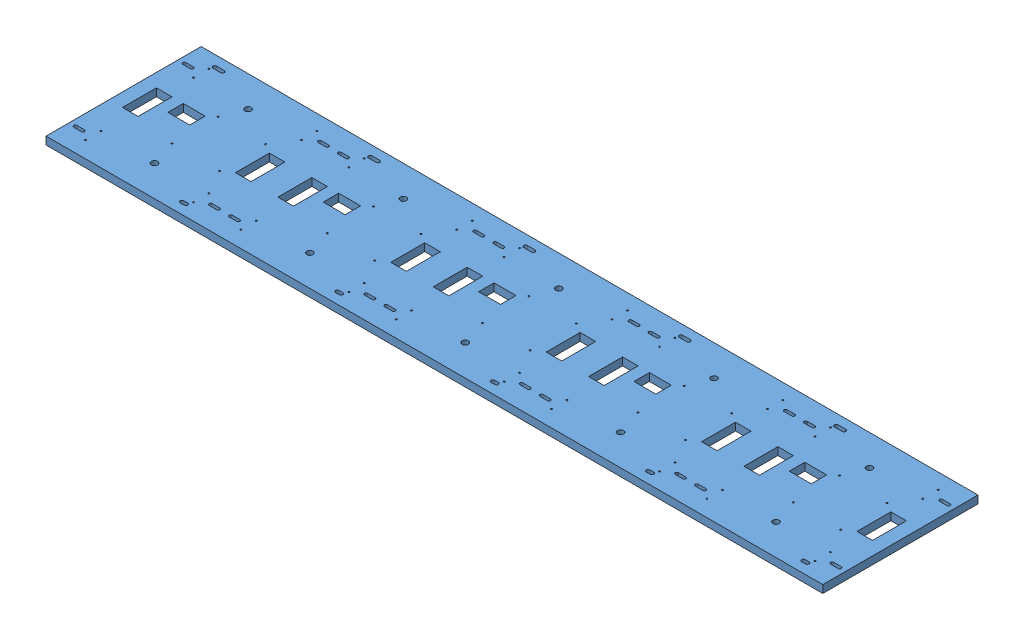
SolidWorks assembly Assem2, configuration Default. Lengths in mm.
Overall size (639.95 6.35 127.84).
6 component instances, 2 part files, 16 mates.
Components (placement in the parent):
- MDF-1: MDF [Default] at (-109.0147 9.1938 79.272) size (127.99 6.35 127.84) (hidden)
- MDF-2: MDF [Default] at (-237.0053 9.1938 79.272) size (127.99 6.35 127.84) (hidden)
- MDF-3: MDF [Default] at (18.9759 9.1938 79.272) size (127.99 6.35 127.84) (hidden)
- MDF-4: MDF [Default] at (274.9571 9.1938 79.272) size (127.99 6.35 127.84) (hidden)
- MDF-5: MDF [Default] at (146.9665 9.1938 79.272) size (127.99 6.35 127.84) (hidden)
- Part4^Assem2-1: Part4^Assem2 [Default] at (146.9665 15.5438 79.272) x (1 0 0) z (0 1 0) size (639.95 127.84 6.35) (virtual)
Mates (geometry in assembly coordinates):
- Coincident1: coincident aligned: plane of MDF-1 through (-109.0147 15.5438 79.272) normal (0 1 0); plane of MDF-2 through (-237.0053 15.5438 79.272) normal (0 1 0)
- Coincident2: coincident aligned: plane of MDF-1 through (-109.0147 15.5438 79.272) normal (0 0 1); plane of MDF-2 through (-237.0053 15.5438 79.272) normal (0 0 1)
- Coincident3: coincident anti-aligned: plane of MDF-1 through (-109.0147 15.5438 79.272) normal (-1 0 0); plane of MDF-2 through (-109.0147 15.5438 79.272) normal (1 0 0)
- Coincident4: coincident aligned: plane of MDF-1 through (-109.0147 15.5438 79.272) normal (0 1 0); plane of MDF-3 through (18.9759 15.5438 79.272) normal (0 1 0)
- Coincident5: coincident aligned: plane of MDF-1 through (-109.0147 15.5438 79.272) normal (0 0 1); plane of MDF-3 through (18.9759 15.5438 79.272) normal (0 0 1)
- Coincident6: coincident anti-aligned: plane of MDF-1 through (18.9759 15.5438 79.272) normal (1 0 0); plane of MDF-3 through (18.9759 15.5438 79.272) normal (-1 0 0)
- Coincident7: coincident anti-aligned: plane of MDF-3 through (146.9665 15.5438 79.272) normal (1 0 0); plane of MDF-5 through (146.9665 15.5438 79.272) normal (-1 0 0)
- Coincident8: coincident aligned: plane of MDF-3 through (18.9759 15.5438 79.272) normal (0 0 1); plane of MDF-5 through (146.9665 15.5438 79.272) normal (0 0 1)
- Coincident9: coincident aligned: plane of MDF-3 through (18.9759 15.5438 79.272) normal (0 1 0); plane of MDF-5 through (146.9665 15.5438 79.272) normal (0 1 0)
- Coincident10: coincident aligned: plane of MDF-4 through (274.9571 15.5438 79.272) normal (0 1 0); plane of MDF-5 through (146.9665 15.5438 79.272) normal (0 1 0)
- Coincident11: coincident aligned: plane of MDF-4 through (274.9571 15.5438 79.272) normal (0 0 1); plane of MDF-5 through (146.9665 15.5438 79.272) normal (0 0 1)
- Coincident12: coincident anti-aligned: plane of MDF-4 through (274.9571 15.5438 79.272) normal (-1 0 0); plane of MDF-5 through (274.9571 15.5438 79.272) normal (1 0 0)
- InPlace1: in place: plane of MDF-5 through (146.9665 15.5438 79.272) normal (0 1 0); plane of ? through (0 15.5438 0) normal (0 1 0); moOrthogonalPlaneRef_w of MDF-5 through (146.9665 15.5438 79.272) normal (0 1 0); plane of ? through (0 15.5438 0) normal (0 0 -1); plane of MDF-5 through (146.9665 15.5438 79.272) normal (0 1 0); line of ? through (-55 0 15.5438) axis (0 1 0); plane of MDF-5 through (146.9665 15.5438 79.272) normal (0 1 0); unknown of Part4^Assem2-1
- Coincident13: coincident aligned: plane of MDF-5; plane of Part4^Assem2-1
- Coincident14: coincident aligned: moOrthogonalPlaneRef_w of MDF-5 through (146.9665 15.5438 79.272) normal (0 0 -1); plane of Part4^Assem2-1 through (146.9665 15.5438 79.272) normal (0 0 -1)
- Coincident15: coincident anti-aligned: moOrthogonalPlaneRef_w of MDF-5 through (146.9665 15.5438 79.272) normal (-1 0 0); plane of Part4^Assem2-1
